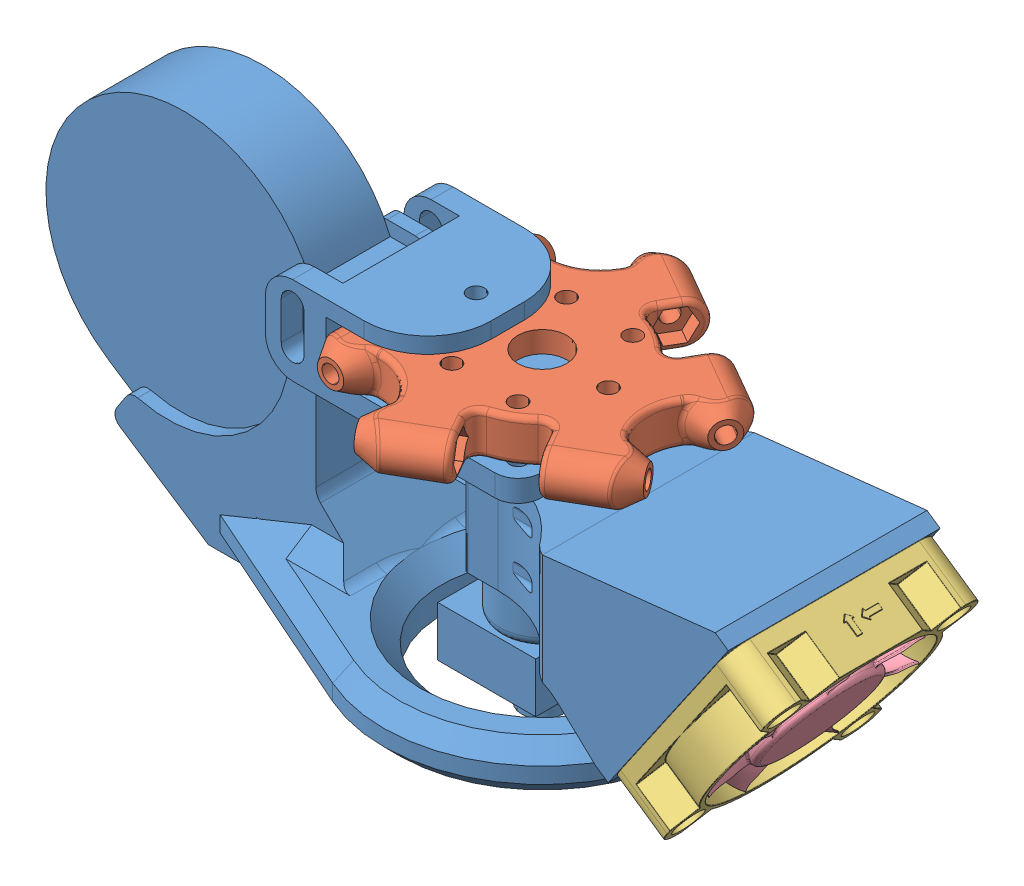
SolidWorks assembly assembled_hotend_jhead, configuration Default. Lengths in mm.
Overall size (150.32 70.35 60).
5 component instances, 4 part files, 6 mates.
Components (placement in the parent):
- jhead-fans-2: jhead-fans [Default] at origin size (141.35 70.35 60)
- effector-2: effector [Groovemount] at (0 9.6 0) size (53.68 8.59 59.75)
- 40mm-fan-1: 40mm-fan [По умолчанию] at (50.2137 -10.5077 -0.9289) x (0 0 1) z (0.823789 -0.566897 0) size (40.01 40.11 10.82)
  - body^40mm-fan-1: body^40mm-fan [По умолчанию] at (0.9289 7.0036 0) size (40.01 40.11 10.81) (virtual)
  - blades^40mm-fan-1: blades^40mm-fan [По умолчанию] at (0.9289 7.0036 -1) size (37.4 37 9.12) (virtual)
Mates (geometry in assembly coordinates):
- Coincident3: coincident anti-aligned: plane of jhead-fans-2 through (-8 9.6 0) normal (0 1 0); plane of effector-2 through (0 9.6 0) normal (0 -1 0)
- Concentric3: concentric anti-aligned: cylinder of jhead-fans-2 through (0 9.6 0) axis (0 1 0) radius 8; cylinder of effector-2 through (0 13.8954 0) axis (0 -1 0) radius 4.625
- Concentric4: concentric aligned: cylinder of jhead-fans-2 through (-12.5 -19.5328 0) axis (0 1 0) radius 1.6; cylinder of effector-2 through (-12.5 5.6 0) axis (0 1 0) radius 1.6
- Coincident4: coincident: plane of jhead-fans-2 through (55.1099 1.8993 -20) normal (0.823789 -0.566897 0); plane of 40mm-fan-1/body^40mm-fan-1 through (50.9398 -4.1605 -11.4014) normal (-0.823789 0.566897 0)
- Concentric10: concentric: cylinder of jhead-fans-2 through (50.2062 0.4182 16) axis (0.823789 -0.566897 0) radius 1.375; cylinder of 40mm-fan-1/body^40mm-fan-1 through (59.3502 -5.8743 16) axis (-0.823789 0.566897 0) radius 1.5
- Concentric11: concentric anti-aligned: cylinder of jhead-fans-2 through (50.2062 0.4182 -16) axis (0.823789 -0.566897 0) radius 1.375; cylinder of 40mm-fan-1/body^40mm-fan-1 through (59.3502 -5.8743 -16) axis (-0.823789 0.566897 0) radius 1.5
